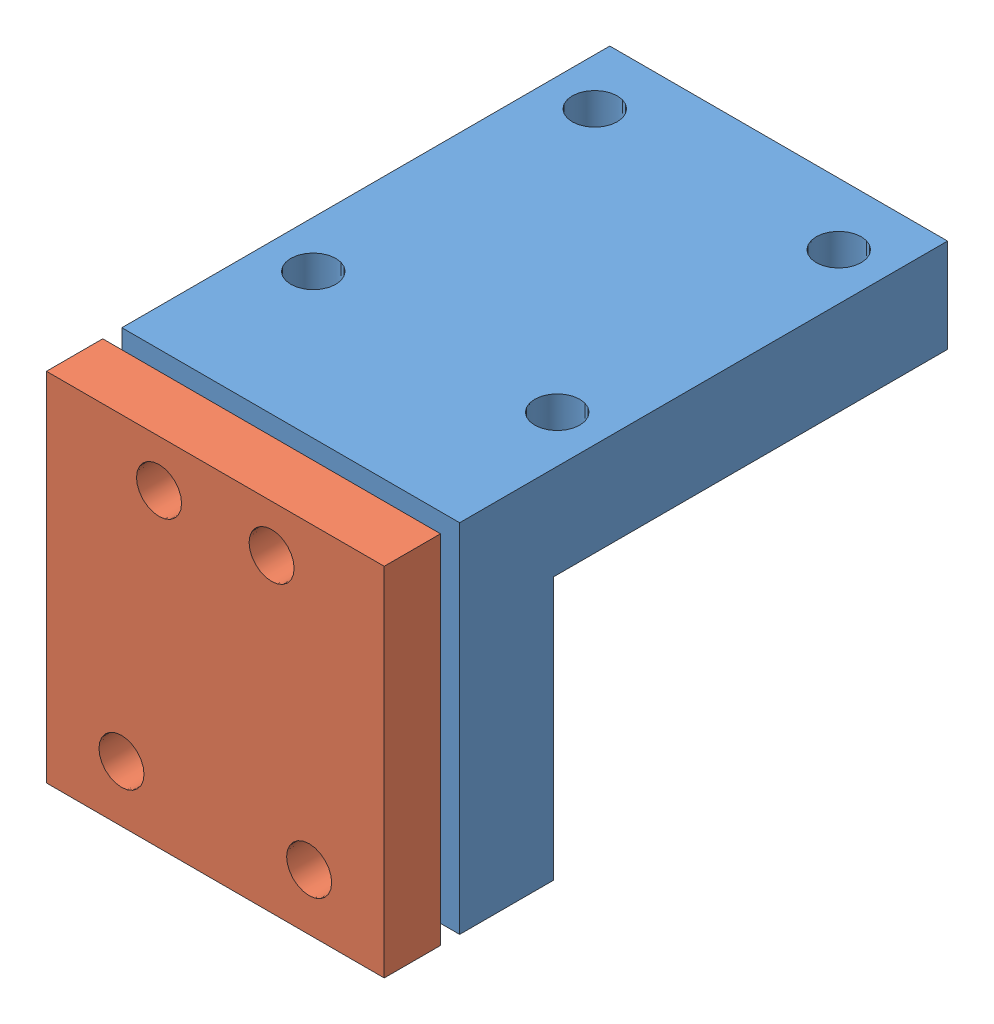
SolidWorks assembly aperto_total, configuration Default. Lengths in mm.
Overall size (18 19 30.02).
2 component instances, 2 part files, 3 mates.
Components (placement in the parent):
- aperto-1: aperto [Default] at (-7.0935 8.6129 9.0395) size (18 19 26)
- aperto_chapa-1: aperto_chapa [Default] at (-7.0935 -5.3871 10.0595) size (18 19 3)
Mates (geometry in assembly coordinates):
- Distance1: distance = 1.02 mm anti-aligned: plane of aperto-1 through (-7.0935 13.6129 9.0395) normal (0 0 1); plane of aperto_chapa-1 through (-7.0935 13.6129 10.0595) normal (0 0 -1)
- Concentric1: concentric aligned: cylinder of aperto-1 through (-1.0935 11.1129 9.0395) axis (0 0 1) radius 0.8; cylinder of aperto_chapa-1 through (-1.0935 11.1129 13.0595) axis (0 0 1) radius 1.2
- Concentric3: concentric aligned: cylinder of aperto-1 through (4.9065 11.1129 9.0395) axis (0 0 1) radius 0.8; cylinder of aperto_chapa-1 through (4.9065 11.1129 13.0595) axis (0 0 1) radius 1.2
